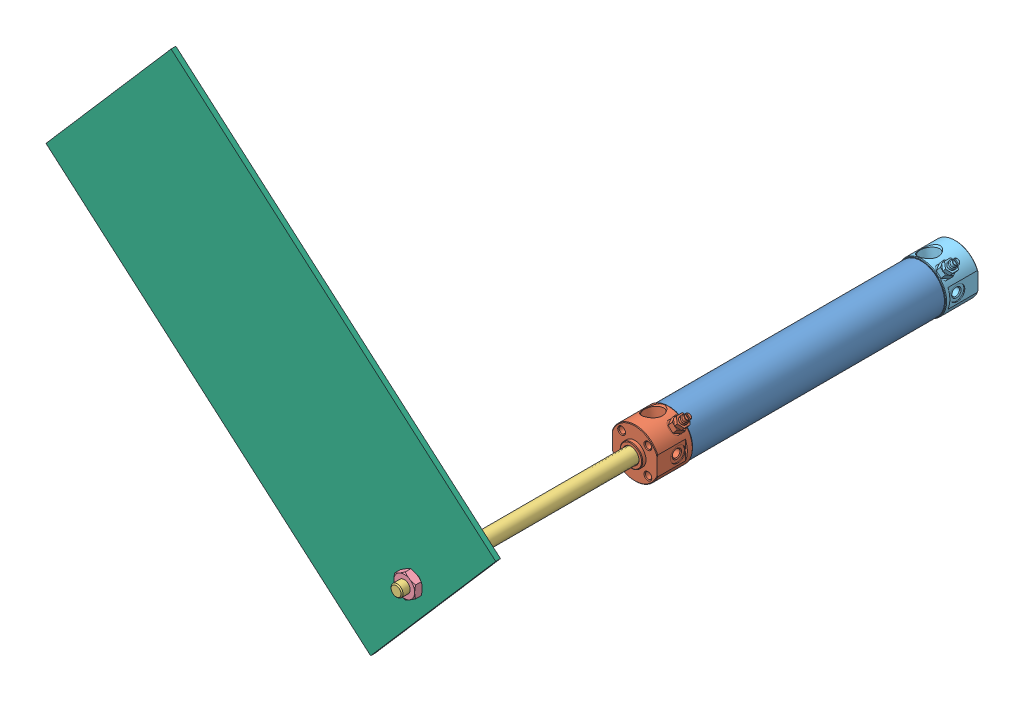
SolidWorks assembly Arm Idea 1, configuration Default. Lengths in mm.
Overall size (239.28 226.52 299.72).
7 component instances, 6 part files, 2 mates.
Components (placement in the parent):
- am-3304 OCG13_4x4_Open-Extend.stp-1: am-3304 OCG13_4x4_Open-Extend.stp [Default] at (110.4458 157.3352 165.3586) size (28.36 30.91 299.72)
  - _TUBE_OCG13_4x4_Open-Extend_.stp-1: _TUBE_OCG13_4x4_Open-Extend_.stp [Default] at origin size (24.99 24.99 134.67)
  - _HD_OCG13_4x4_Open-Extend.stp-1: _HD_OCG13_4x4_Open-Extend.stp [Default] at (0 0 67.3354) size (28.36 30.91 20.04)
  - _PR_OCG1-3_4x4.stp-1: _PR_OCG1-3_4x4.stp [Default] at (0 0 199.644) size (19.02 19.02 170.07)
  - _PN1972-015_NUT1_4-28-UNF.stp-1: _PN1972-015_NUT1_4-28-UNF.stp [Default] at (0 0 204.0128) x (0 0 1) z (-1 0 0) size (3.99 12.86 11.14)
  - _CAP_OCG1-3_4.stp-1: _CAP_OCG1-3_4.stp [Default] at (0 0 -67.3354) size (28.36 30.91 20.04)
- Grab Plate-1: Grab Plate [Default] at (33.6823 223.8928 367.5426) x (0 0 1) z (0.755546 -0.655095 0) size (2.54 101.6 228.6)
Mates (geometry in assembly coordinates):
- Concentric1: concentric aligned: cylinder of am-3304 OCG13_4x4_Open-Extend.stp-1/_PR_OCG1-3_4x4.stp-1 through (110.4458 157.3352 207.6305) axis (0 0 1) radius 3.175; cylinder of Grab Plate-1 through (110.4458 157.3352 365.0016) axis (0 0 1) radius 3.175
- Coincident1: coincident aligned: circle of am-3304 OCG13_4x4_Open-Extend.stp-1/_PR_OCG1-3_4x4.stp-1; plane of Grab Plate-1 through (33.6823 223.8928 365.0026) normal (0 0 -1)
